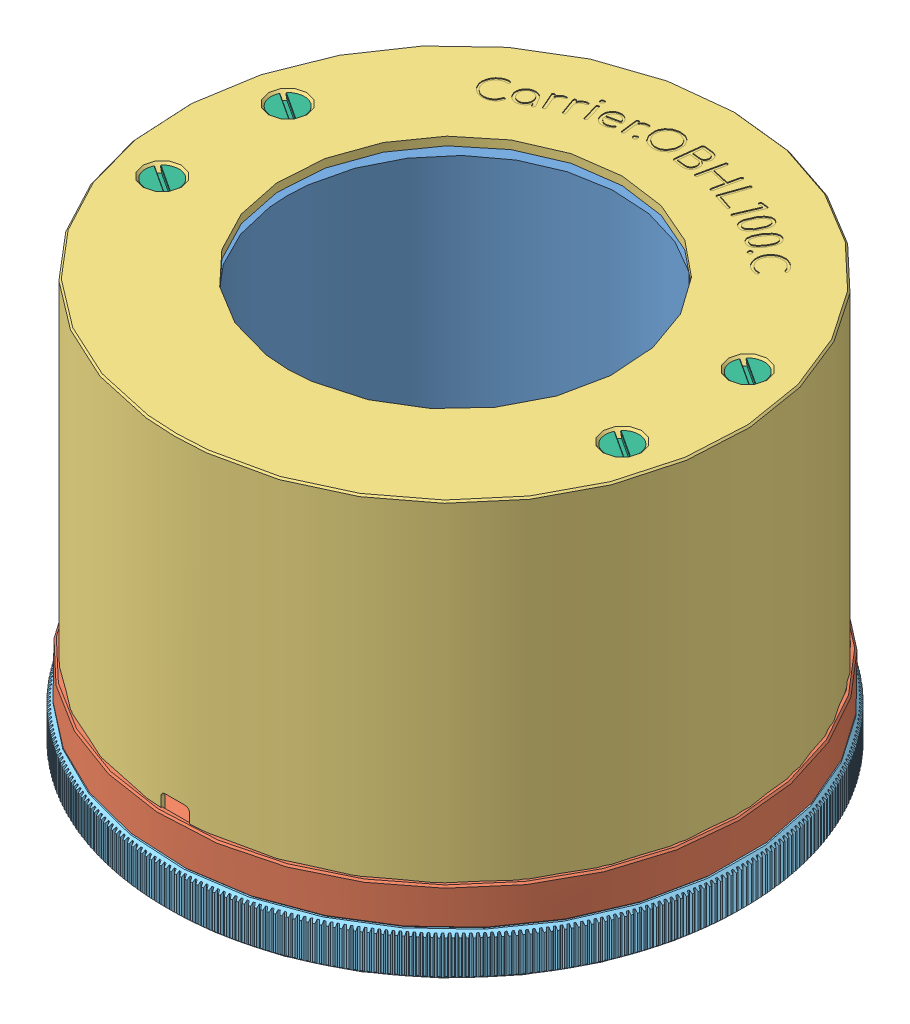
SolidWorks assembly Carrier.OB100.HL打标, configuration Default. Lengths in mm.
Overall size (93.68 54 93.68).
9 component instances, 6 part files, 16 mates.
Components (placement in the parent):
- 复件 InnerTube_ver9_1^Carrier.OB100.HL打标-1: 复件 InnerTube_ver9_1^Carrier.OB100.HL打标 [Default] at (0 0.5 0) x (0 0 1) z (-1 0 0) size (44 38.5 44) (virtual)
- 复件 BasePiece_ver9^Carrier.OB100.HL打标-1: 复件 BasePiece_ver9^Carrier.OB100.HL打标 [Default] at (0 -3 0) x (0 0 1) z (-1 0 0) size (68 9 68) (virtual)
- 复件 OuterCasing_ver9^Carrier.OB100.HL打标-1: 复件 OuterCasing_ver9^Carrier.OB100.HL打标 [Default] at (0 1 0) x (1 0 -0.000303) z (0.000303 0 1) size (67 40 67) (virtual)
- 复件 lock ring_1^Carrier.OB100.HL打标-1: 复件 lock ring_1^Carrier.OB100.HL打标 [Default] at (0 -3 0) x (0.929896 0 -0.367822) z (-0.367822 0 -0.929896) size (38.58 10.28 38.25) (virtual)
- 复件 lock ring_handle_1^Carrier.OB100.HL打标-1: 复件 lock ring_handle_1^Carrier.OB100.HL打标 [Default] at (0 -8 0) x (0.480967 0 0.876739) z (-0.876739 0 0.480967) size (69 5.71 69) (virtual)
- 复件 M2.5沉头^Carrier.OB100.HL打标-2: 复件 M2.5沉头^Carrier.OB100.HL打标 [Default] at (27.4977 39.95 7.4917) x (-0.837169 0 -0.546944) z (-0.546944 0 0.837169) size (3.97 5.8 4) (virtual)
- 复件 M2.5沉头^Carrier.OB100.HL打标-3: 复件 M2.5沉头^Carrier.OB100.HL打标 [Default] at (-27.4932 39.95 7.5083) x (-0.837169 0 -0.546944) z (-0.546944 0 0.837169) size (3.97 5.8 4) (virtual)
- 复件 M2.5沉头^Carrier.OB100.HL打标-4: 复件 M2.5沉头^Carrier.OB100.HL打标 [Default] at (-27.4977 39.95 -7.4917) x (-0.837169 0 -0.546944) z (-0.546944 0 0.837169) size (3.97 5.8 4) (virtual)
- 复件 M2.5沉头^Carrier.OB100.HL打标-5: 复件 M2.5沉头^Carrier.OB100.HL打标 [Default] at (27.4932 39.95 -7.5083) x (-0.837169 0 -0.546944) z (-0.546944 0 0.837169) size (3.97 5.8 4) (virtual)
Mates (geometry in assembly coordinates):
- 同心13: concentric anti-aligned: cylinder of BasePiece_ver9-1 through (0 1.5 0) axis (0 -1 0) radius 13.5; cylinder of 复件 lock ring_1^Carrier.S100_OB.Z.HL-1 through (0 -7.5 0) axis (0 1 0) radius 16
- 重合29: coincident anti-aligned: plane of BasePiece_ver9-1 through (0 -3 0) normal (0 -1 0); plane of 复件 lock ring_1^Carrier.S100_OB.Z.HL-1 through (0 -3 0) normal (0 1 0)
- 同心14: concentric anti-aligned: cylinder of 复件 lock ring_1^Carrier.S100_OB.Z.HL-1 through (0 -7.5 0) axis (0 1 0) radius 18.5; cylinder of 复件 lock ring_handle_1^Carrier.S100_OB.Z.HL-1 through (0 -3 0) axis (0 -1 0) radius 18.5
- 重合30: coincident anti-aligned: plane of BasePiece_ver9-1 through (0 -3 0) normal (0 -1 0); plane of 复件 lock ring_handle_1^Carrier.S100_OB.Z.HL-1 through (0 -3 0) normal (0 1 0)
- 同心17: concentric aligned: cylinder of 复件 InnerTube_ver9_1^Carrier.S100_OB.Z.HL-1 through (0 39 0) axis (0 -1 0) radius 22; cylinder of 复件 BasePiece_ver9^Carrier.S100_OB.Z.HL-1 through (0 0 0) axis (0 -1 0) radius 34
- 距离1: distance = 0.5 mm anti-aligned: plane of 复件 BasePiece_ver9^Carrier.S100_OB.Z.HL-1 through (0 0 0) normal (0 1 0); plane of 复件 InnerTube_ver9_1^Carrier.S100_OB.Z.HL-1 through (0 0.5 0) normal (0 -1 0)
- 同心18: concentric aligned: cylinder of 复件 InnerTube_ver9_1^Carrier.S100_OB.Z.HL-1 through (0 39 0) axis (0 -1 0) radius 22; cylinder of 复件 OuterCasing_ver9^Carrier.OB100.HL-1 through (0 41 0) axis (0 -1 0) radius 33.5
- 距离2: distance = 1 mm anti-aligned: plane of 复件 OuterCasing_ver9^Carrier.OB100.HL-1 through (0 1 0) normal (0 -1 0); plane of 复件 BasePiece_ver9^Carrier.S100_OB.Z.HL-1 through (0 0 0) normal (0 1 0)
- 同心19: concentric anti-aligned: cone of 复件 OuterCasing_ver9^Carrier.OB100.HL-1 through (27.4977 40 7.4917) axis (0 -1 0); cylinder of 复件 M2.5沉头^Carrier.OB100.HL-2 through (27.4977 34.95 7.4917) axis (0 1 0) radius 1.25
- 重合34: coincident aligned: cylinder of 复件 OuterCasing_ver9^Carrier.OB100.HL-1 through (27.4977 40 7.4917) axis (0 -1 0) radius 785.3982; cylinder of 复件 M2.5沉头^Carrier.S100_OB.Z.HL-2 through (27.4977 40.7 7.4917) axis (0 -1 0) radius 785.3982
- 同心20: concentric anti-aligned: cylinder of 复件 OuterCasing_ver9^Carrier.OB100.HL-1 through (27.4932 40 -7.5083) axis (0 -1 0) radius 785.3982; cylinder of 复件 M2.5沉头^Carrier.OB100.HL-5 through (27.4932 34.95 -7.5083) axis (0 1 0) radius 1.25
- 同心21: concentric anti-aligned: cylinder of 复件 OuterCasing_ver9^Carrier.OB100.HL-1 through (-27.4977 40 -7.4917) axis (0 -1 0) radius 785.3982; cylinder of 复件 M2.5沉头^Carrier.OB100.HL-4 through (-27.4977 34.95 -7.4917) axis (0 1 0) radius 1.25
- 同心22: concentric anti-aligned: cylinder of 复件 OuterCasing_ver9^Carrier.OB100.HL-1 through (-27.4932 40 7.5083) axis (0 -1 0) radius 785.3982; cylinder of 复件 M2.5沉头^Carrier.OB100.HL-3 through (-27.4932 34.95 7.5083) axis (0 1 0) radius 1.25
- 重合35: coincident aligned: plane of 复件 M2.5沉头^Carrier.OB100.HL-2 through (27.4977 40.75 7.4917) normal (0 1 0); plane of 复件 M2.5沉头^Carrier.OB100.HL-5 through (27.4932 40.75 -7.5083) normal (0 1 0)
- 重合36: coincident aligned: plane of 复件 M2.5沉头^Carrier.OB100.HL-2 through (27.4977 40.75 7.4917) normal (0 1 0); plane of 复件 M2.5沉头^Carrier.OB100.HL-4 through (-27.4977 40.75 -7.4917) normal (0 1 0)
- 重合37: coincident aligned: plane of 复件 M2.5沉头^Carrier.OB100.HL-2 through (27.4977 40.75 7.4917) normal (0 1 0); plane of 复件 M2.5沉头^Carrier.OB100.HL-3 through (-27.4932 40.75 7.5083) normal (0 1 0)
